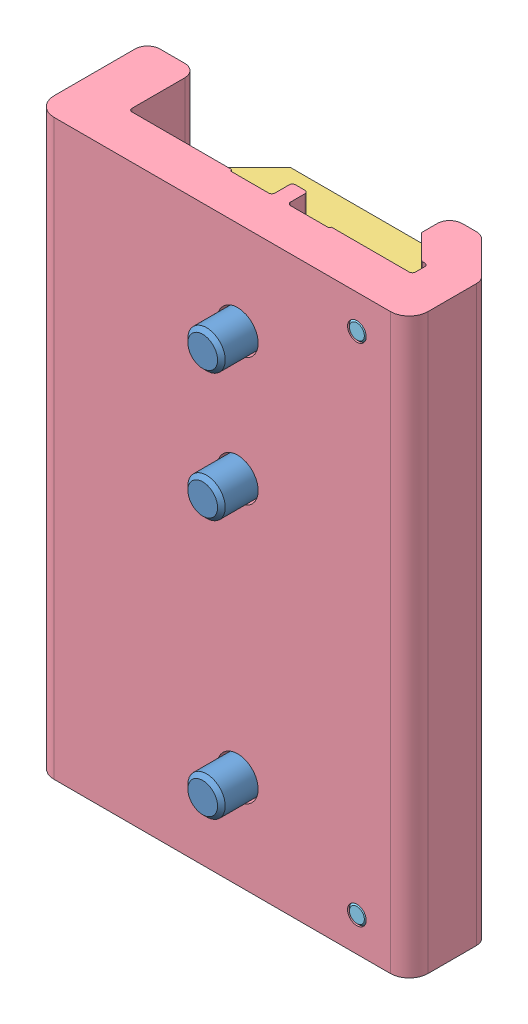
SolidWorks assembly 2046989-S074065, configuration Default. Lengths in mm.
Overall size (94.51 129.76 118.53).
9 component instances, 5 part files, 0 mates.
Components (placement in the parent):
- 5305380_Senkschraube_DIN7991_M6x12_01-1: 5305380_Senkschraube_DIN7991_M6x12_01 [Default] at (0 10.5 -17.4) x (0 0 1) z (-0.471406 -0.881916 0) size (12 12 12)
- 5305380_Senkschraube_DIN7991_M6x12_01-2: 5305380_Senkschraube_DIN7991_M6x12_01 [Default] at (0 31 -17.4) x (0 0 1) z (-0.471406 -0.881916 0) size (12 12 12)
- 5305380_Senkschraube_DIN7991_M6x12_01-3: 5305380_Senkschraube_DIN7991_M6x12_01 [Default] at (0 -31 -17.4) x (0 0 1) z (-0.471406 -0.881916 0) size (12 12 12)
- 5305381_Gewindestift_DIN914_M8x16_01-1: 5305381_Gewindestift_DIN914_M8x16_01 [Default] at (-34.9632 31 -18.5) x (1 0 0) z (0 -0.44067 -0.897669) size (16 8 8)
- 4055142_Klemmstueck-1: 4055142_Klemmstueck [Default] at (-412.8 -1936.9236 -1331.6968) x (0.122788 0.696364 0.707107) z (0.984808 -0.173648 0) size (66.55 66.55 52.94)
- 4055143_Klemmprofil_bearbeitet-1: 4055143_Klemmprofil_bearbeitet [Default] at (412.8736 1904.9236 -1331.6968) x (-0.122788 -0.696364 0.707107) z (-0.984808 0.173648 0) size (83.45 84.17 75.07)
- 5305381_Gewindestift_DIN914_M8x16_01-2: 5305381_Gewindestift_DIN914_M8x16_01 [Default] at (-34.9632 -31 -18.5) x (1 0 0) z (0 -0.44067 -0.897669) size (16 8 8)
- S004024_StiftZyl3M6x16_ISO_2338.2-1: S004024_StiftZyl3M6x16_ISO_2338.2 [Default] at (-408.9364 -12.8322 499.2206) x (-1 0 0) z (0 1 0) size (3 16 3)
- S004024_StiftZyl3M6x16_ISO_2338.2-2: S004024_StiftZyl3M6x16_ISO_2338.2 [Default] at (-408.9364 68.2678 499.2206) x (-1 0 0) z (0 1 0) size (3 16 3)
